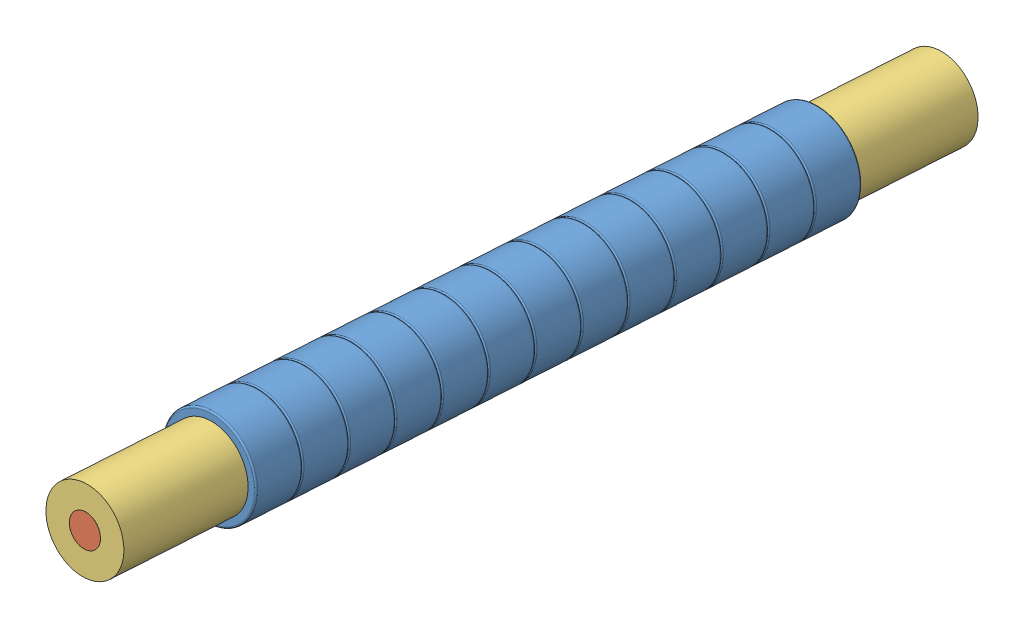
SolidWorks assembly longerbearing, configuration Default. Lengths in mm.
Overall size (8.41 9.28 55.2).
16 component instances, 3 part files, 30 mates.
Components (placement in the parent):
- ballbearing-1: ballbearing [Default] at (14.4511 -62.7163 8.7936) x (0 0.061017 0.998137) z (-0.364148 0.929606 -0.056828) size (3 6 6)
- ballbearing-2: ballbearing [Default] at (14.4511 -64.9129 -27.1393) x (0 0.061017 0.998137) z (-0.008288 0.998102 -0.061015) size (3 6 6)
- ballbearing-3: ballbearing [Default] at (14.4511 -64.3638 -18.156) x (0 0.061017 0.998137) z (-0.040464 0.997319 -0.060967) size (3 6 6)
- ballbearing-4: ballbearing [Default] at (14.4511 -62.8994 5.7992) x (0 0.061017 0.998137) z (-0.050452 0.996866 -0.060939) size (3 6 6)
- ballbearing-5: ballbearing [Default] at (14.4511 -64.7299 -24.1449) x (0 0.061017 0.998137) z (-0.050452 0.996866 -0.060939) size (3 6 6)
- ballbearing-6: ballbearing [Default] at (14.4511 -64.1807 -15.1616) x (0 0.061017 0.998137) z (-0.050452 0.996866 -0.060939) size (3 6 6)
- ballbearing-7: ballbearing [Default] at (14.4511 -64.5468 -21.1505) x (0 0.061017 0.998137) z (-0.050452 0.996866 -0.060939) size (3 6 6)
- ballbearing-8: ballbearing [Default] at (14.4511 -63.9977 -12.1672) x (0 0.061017 0.998137) z (-0.977727 0.209492 -0.012806) size (3 6 6)
- ballbearing-9: ballbearing [Default] at (14.4511 -63.0824 2.8048) x (0 0.061017 0.998137) z (-0.911074 0.411474 -0.025154) size (3 6 6)
- Copy of Copy of Copy of Part3^longerbearing-1: Copy of Copy of Copy of Part3^longerbearing [Default] at (-17.4526 -45.0547 -36.3682) x (0.009245 -0.998094 0.061014) z (0 0.061017 0.998137) size (2 2 55) (virtual)
- ballbearing-10: ballbearing [Default] at (14.4511 -63.8146 -9.1728) x (0 0.061017 0.998137) z (-0.911074 0.411474 -0.025154) size (3 6 6)
- ballbearing-11: ballbearing [Default] at (14.4511 -63.4485 -3.184) x (0 0.061017 0.998137) z (-0.796119 0.604012 -0.036924) size (3 6 6)
- ballbearing-12: ballbearing [Default] at (14.4511 -63.6316 -6.1784) x (0 0.061017 0.998137) z (-0.897579 0.440032 -0.0269) size (3 6 6)
- ballbearing-13: ballbearing [Default] at (14.4511 -63.2655 -0.1896) x (0 0.061017 0.998137) z (-0.911074 0.411474 -0.025154) size (3 6 6)
- Spacer-1: Spacer [Default] at (14.4511 -65.4011 -35.1244) x (1 0 0) z (0 0.061017 0.998137) size (5 5 8)
- Spacer-2: Spacer [Default] at (14.4511 -62.5333 11.7881) x (1 0 0) z (0 0.061017 0.998137) size (5 5 8)
Mates (geometry in assembly coordinates):
- Concentric3: concentric aligned: cylinder of ballbearing-1 through (14.4511 -62.5333 11.7881) axis (0 -0.061017 -0.998137) radius 1; cylinder of Copy of Copy of Copy of Part3^longerbearing-1 through (14.4511 -62.0451 19.7731) axis (0 -0.061017 -0.998137) radius 1
- Coincident9: coincident anti-aligned: plane of ballbearing-1 through (14.4511 -62.7163 8.7936) normal (0 -0.061017 -0.998137); plane of ballbearing-4 through (14.4511 -62.7163 8.7936) normal (0 0.061017 0.998137)
- Coincident10: coincident anti-aligned: plane of ballbearing-2 through (14.4511 -64.7299 -24.1449) normal (0 0.061017 0.998137); plane of ballbearing-5 through (14.4511 -64.7299 -24.1449) normal (0 -0.061017 -0.998137)
- Concentric8: concentric aligned: cylinder of ballbearing-2 through (14.4511 -64.7299 -24.1449) axis (0 -0.061017 -0.998137) radius 1; cylinder of Copy of Copy of Copy of Part3^longerbearing-1 through (14.4511 -62.0451 19.7731) axis (0 -0.061017 -0.998137) radius 1
- Concentric5: concentric aligned: cylinder of ballbearing-3 through (14.4511 -64.1807 -15.1616) axis (0 -0.061017 -0.998137) radius 1; cylinder of Copy of Copy of Copy of Part3^longerbearing-1 through (14.4511 -62.0451 19.7731) axis (0 -0.061017 -0.998137) radius 1
- Coincident12: coincident anti-aligned: plane of ballbearing-3 through (14.4511 -64.1807 -15.1616) normal (0 0.061017 0.998137); plane of ballbearing-6 through (14.4511 -64.1807 -15.1616) normal (0 -0.061017 -0.998137)
- Coincident14: coincident anti-aligned: plane of ballbearing-3 through (14.4511 -64.3638 -18.156) normal (0 -0.061017 -0.998137); plane of ballbearing-7 through (14.4511 -64.3638 -18.156) normal (0 0.061017 0.998137)
- Concentric6: concentric aligned: cylinder of Copy of Copy of Copy of Part3^longerbearing-1 through (14.4511 -62.0451 19.7731) axis (0 -0.061017 -0.998137) radius 1; cylinder of ballbearing-4 through (14.4511 -62.7163 8.7936) axis (0 -0.061017 -0.998137) radius 1
- Coincident16: coincident anti-aligned: plane of ballbearing-4 through (14.4511 -62.8994 5.7992) normal (0 -0.061017 -0.998137); plane of ballbearing-9 through (14.4511 -62.8994 5.7992) normal (0 0.061017 0.998137)
- Concentric7: concentric aligned: cylinder of Copy of Copy of Copy of Part3^longerbearing-1 through (14.4511 -62.0451 19.7731) axis (0 -0.061017 -0.998137) radius 1; cylinder of ballbearing-5 through (14.4511 -64.5468 -21.1505) axis (0 -0.061017 -0.998137) radius 1
- Coincident13: coincident anti-aligned: plane of ballbearing-5 through (14.4511 -64.5468 -21.1505) normal (0 0.061017 0.998137); plane of ballbearing-7 through (14.4511 -64.5468 -21.1505) normal (0 -0.061017 -0.998137)
- Concentric9: concentric aligned: cylinder of Copy of Copy of Copy of Part3^longerbearing-1 through (14.4511 -62.0451 19.7731) axis (0 -0.061017 -0.998137) radius 1; cylinder of ballbearing-6 through (14.4511 -63.9977 -12.1672) axis (0 -0.061017 -0.998137) radius 1
- Coincident15: coincident anti-aligned: plane of ballbearing-6 through (14.4511 -63.9977 -12.1672) normal (0 0.061017 0.998137); plane of ballbearing-8 through (14.4511 -63.9977 -12.1672) normal (0 -0.061017 -0.998137)
- Concentric10: concentric aligned: cylinder of Copy of Copy of Copy of Part3^longerbearing-1 through (14.4511 -62.0451 19.7731) axis (0 -0.061017 -0.998137) radius 1; cylinder of ballbearing-7 through (14.4511 -64.3638 -18.156) axis (0 -0.061017 -0.998137) radius 1
- Concentric11: concentric aligned: cylinder of Copy of Copy of Copy of Part3^longerbearing-1 through (14.4511 -62.0451 19.7731) axis (0 -0.061017 -0.998137) radius 1; cylinder of ballbearing-8 through (14.4511 -63.8146 -9.1728) axis (0 -0.061017 -0.998137) radius 1
- Concentric12: concentric aligned: cylinder of ballbearing-9 through (14.4511 -62.8994 5.7992) axis (0 -0.061017 -0.998137) radius 1; cylinder of Copy of Copy of Copy of Part3^longerbearing-1 through (14.4511 -62.0451 19.7731) axis (0 -0.061017 -0.998137) radius 1
- Concentric13: concentric aligned: cylinder of Copy of Copy of Copy of Part3^longerbearing-1 through (14.4511 -62.0451 19.7731) axis (0 -0.061017 -0.998137) radius 1; cylinder of ballbearing-10 through (14.4511 -63.6316 -6.1784) axis (0 -0.061017 -0.998137) radius 1
- Coincident17: coincident anti-aligned: plane of ballbearing-8 through (14.4511 -63.8146 -9.1728) normal (0 0.061017 0.998137); plane of ballbearing-10 through (14.4511 -63.8146 -9.1728) normal (0 -0.061017 -0.998137)
- Concentric14: concentric aligned: cylinder of Copy of Copy of Copy of Part3^longerbearing-1 through (14.4511 -62.0451 19.7731) axis (0 -0.061017 -0.998137) radius 1; cylinder of ballbearing-13 through (14.4511 -63.0824 2.8048) axis (0 -0.061017 -0.998137) radius 1
- Coincident18: coincident anti-aligned: plane of ballbearing-9 through (14.4511 -63.0824 2.8048) normal (0 -0.061017 -0.998137); plane of ballbearing-13 through (14.4511 -63.0824 2.8048) normal (0 0.061017 0.998137)
- Concentric15: concentric aligned: cylinder of Copy of Copy of Copy of Part3^longerbearing-1 through (14.4511 -62.0451 19.7731) axis (0 -0.061017 -0.998137) radius 1; cylinder of ballbearing-12 through (14.4511 -63.4485 -3.184) axis (0 -0.061017 -0.998137) radius 1
- Coincident19: coincident anti-aligned: plane of ballbearing-10 through (14.4511 -63.6316 -6.1784) normal (0 0.061017 0.998137); plane of ballbearing-12 through (14.4511 -63.6316 -6.1784) normal (0 -0.061017 -0.998137)
- Concentric16: concentric aligned: cylinder of Copy of Copy of Copy of Part3^longerbearing-1 through (14.4511 -62.0451 19.7731) axis (0 -0.061017 -0.998137) radius 1; cylinder of ballbearing-11 through (14.4511 -63.2655 -0.1896) axis (0 -0.061017 -0.998137) radius 1
- Coincident20: coincident anti-aligned: plane of ballbearing-11 through (14.4511 -63.4485 -3.184) normal (0 -0.061017 -0.998137); plane of ballbearing-12 through (14.4511 -63.4485 -3.184) normal (0 0.061017 0.998137)
- Coincident21: coincident anti-aligned: plane of ballbearing-11 through (14.4511 -63.2655 -0.1896) normal (0 0.061017 0.998137); plane of ballbearing-13 through (14.4511 -63.2655 -0.1896) normal (0 -0.061017 -0.998137)
- Concentric17: concentric aligned: cylinder of Copy of Copy of Copy of Part3^longerbearing-1 through (14.4511 -62.0451 19.7731) axis (0 -0.061017 -0.998137) radius 1; cylinder of Spacer-2 through (14.4511 -62.0451 19.7731) axis (0 -0.061017 -0.998137) radius 1
- Concentric18: concentric aligned: cylinder of Copy of Copy of Copy of Part3^longerbearing-1 through (14.4511 -62.0451 19.7731) axis (0 -0.061017 -0.998137) radius 1; cylinder of Spacer-1 through (14.4511 -64.9129 -27.1393) axis (0 -0.061017 -0.998137) radius 1
- Coincident22: coincident anti-aligned: plane of ballbearing-1 through (14.4511 -62.5333 11.7881) normal (0 0.061017 0.998137); plane of Spacer-2 through (14.4511 -62.5333 11.7881) normal (0 -0.061017 -0.998137)
- Coincident24: coincident anti-aligned: plane of ballbearing-2 through (14.4511 -64.9129 -27.1393) normal (0 -0.061017 -0.998137); plane of Spacer-1 through (14.4511 -64.9129 -27.1393) normal (0 0.061017 0.998137)
- Coincident25: coincident aligned: plane of Copy of Copy of Copy of Part3^longerbearing-1 through (14.4511 -62.0451 19.7731) normal (0 0.061017 0.998137); plane of Spacer-2 through (14.4511 -62.0451 19.7731) normal (0 0.061017 0.998137)
